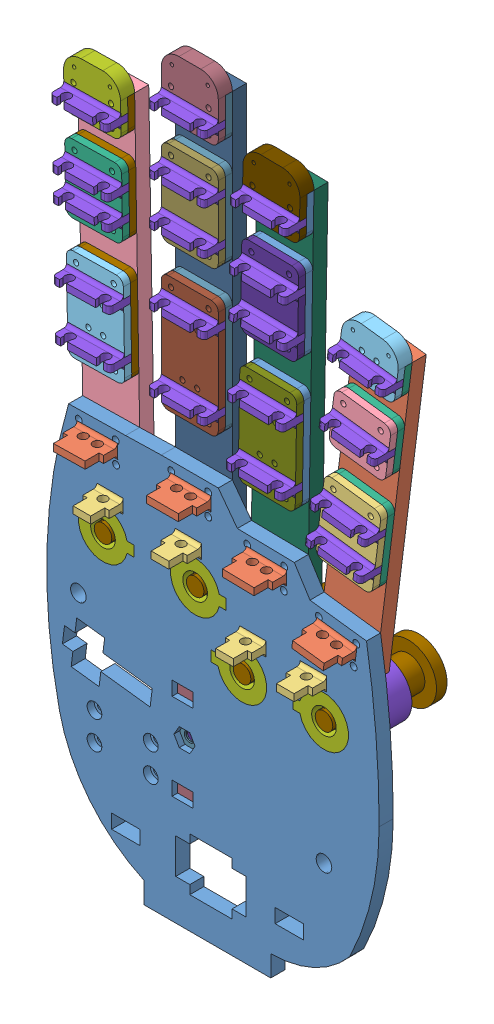
SolidWorks assembly palmUp_fingers_buttons_upPulley, configuration Default. Lengths in mm.
Overall size (100.53 213.84 40.29).
185 component instances, 43 part files, 94 mates.
Components (placement in the parent):
- palmUp-1: palmUp [Default] at (29.1174 30.4931 80.2216) size (94.52 113.2 4)
- driverBaseFrame1-1: driverBaseFrame1 [Default] at (-2.9175 115.1932 80.2216) x (0.999847 0.017467 0) z (0.017467 -0.999847 0) size (11.5 12 4)
- driverBaseFrame1-2: driverBaseFrame1 [Default] at (23.5924 115.6931 80.2216) x (1 0 0) z (0 -1 0) size (11.5 12 4)
- driverBaseFrame1-3: driverBaseFrame1 [Default] at (45.1535 108.3901 80.2216) x (0.999848 -0.017452 0) z (-0.017452 -0.999848 0) size (11.5 12 4)
- driverBaseFrame1-4: driverBaseFrame1 [Default] at (65.1211 100.8452 80.2216) x (0.992117 -0.125312 0) z (-0.125312 -0.992117 0) size (11.5 12 4)
- driverBaseFrame2-1: driverBaseFrame2 [Default] at (-1948.2383 102.6443 -1374.6625) x (1 0 0) z (0 -1 0) size (7.5 12 4)
- driverBaseFrame2-2: driverBaseFrame2 [Default] at (1983.3157 100.6443 -1374.6625) x (-1 0 0) z (0 1 0) size (7.5 12 4)
- driverBaseFrame2-4: driverBaseFrame2 [Default] at (-1907.6963 87.8147 -1374.6625) x (1 0 0) z (0 -1 0) size (7.5 12 4)
- driverBaseFrame2-5: driverBaseFrame2 [Default] at (-1890.412 87.8147 -1374.6625) x (1 0 0) z (0 -1 0) size (7.5 12 4)
- index-1: index [Default] at (-52.494 173.2306 -0.0096) x (-0.999847 -0.017467 0) z (0 0 -1) size (16.2 99.16 12.01)
  - indexElastomer-1: indexElastomer [Default] at (-62.4059 -67.241 -80.2312) size (16.2 94.16 4)
  - indexPIP-1: indexPIP [Default] at (-62.4059 -42.8945 -84.2312) size (16.2 26.26 2)
  - indexMIP-1: indexMIP [Default] at (-62.4059 -8.6345 -84.2312) size (16.2 19.45 2)
  - indexDIP-1: indexDIP [Default] at (-62.4059 16.8205 -84.2312) size (16.2 14.95 4)
  - tubeDriver-6: tubeDriver [Default] at (-62.4059 20.8205 -80.2312) x (1 0 0) z (0 1 0) size (16.2 6 4)
  - tubeDriver-7: tubeDriver [Default] at (-62.4059 3.8205 -80.2312) x (1 0 0) z (0 1 0) size (16.2 6 4)
  - tubeDriver-8: tubeDriver [Default] at (-62.4059 -3.6345 -80.2312) x (1 0 0) z (0 1 0) size (16.2 6 4)
  - tubeDriver-9: tubeDriver [Default] at (-62.4059 -23.6345 -80.2312) x (1 0 0) z (0 1 0) size (16.2 6 4)
  - tubeDriver-10: tubeDriver [Default] at (-62.4059 -37.8945 -80.2312) x (1 0 0) z (0 1 0) size (16.2 6 4)
  - indexTube1-1: indexTube1 [Default] at (-49.2059 -21.6345 -86.4812) x (-0.964902 0 0.26261) z (0 -1 0) size (2.5 2.5 16.26) (hidden)
  - indexTube1-2: indexTube1 [Default] at (-59.4059 -21.6345 -86.4812) x (-0.775159 0 0.631766) z (0 -1 0) size (2.5 2.5 16.26) (hidden)
  - indexTube2-1: indexTube2 [Default] at (-49.2059 5.8205 -86.4812) x (0.360054 0 0.932932) z (0 -1 0) size (2.5 2.5 9.46) (hidden)
  - indexTube2-2: indexTube2 [Default] at (-59.4059 5.8205 -86.4812) x (-0.658969 0 -0.75217) z (0 -1 0) size (2.5 2.5 9.46) (hidden)
  - commonFingersTube-1: commonFingersTube [Default] at (-49.2059 22.8205 -86.4812) x (-0.856421 0 0.516277) z (0 -1 0) size (2.5 2.5 2) (hidden)
  - commonFingersTube-2: commonFingersTube [Default] at (-59.4059 22.8205 -86.4812) x (-0.999231 0 0.039215) z (0 -1 0) size (2.5 2.5 2) (hidden)
  - indexJointBase-1: indexJointBase [Default] at (-62.4059 -67.241 -82.2312) size (16.2 69.66 2)
- middle-1: middle [Default] at (34.8412 175.8995 -30.6566) size (16.2 113.14 12)
  - middleElastomer-1: middleElastomer [Default] at (-13.8237 -68.7065 106.8781) size (16.2 108.14 4)
  - middlePIP-1: middlePIP [Default] at (-13.8237 -44.2065 110.8781) size (16.2 33.21 2)
  - middleMIP-1: middleMIP [Default] at (-13.8237 -2.9965 110.8781) size (16.2 24.45 2)
  - middleDIP-1: middleDIP [Default] at (-5.7237 27.4535 110.8781) size (16.2 16.98 4)
  - tubeDriver-2: tubeDriver [Default] at (-13.8237 33.4535 110.8781) x (1 0 0) z (0 -1 0) size (16.2 6 4)
  - tubeDriver-3: tubeDriver [Default] at (-13.8237 16.4535 110.8781) x (1 0 0) z (0 -1 0) size (16.2 6 4)
  - tubeDriver-4: tubeDriver [Default] at (-13.8237 4.0035 110.8781) x (1 0 0) z (0 -1 0) size (16.2 6 4)
  - tubeDriver-5: tubeDriver [Default] at (-13.8237 -15.9965 110.8781) x (1 0 0) z (0 -1 0) size (16.2 6 4)
  - tubeDriver-6: tubeDriver [Default] at (-13.8237 -37.2065 110.8781) x (1 0 0) z (0 -1 0) size (16.2 6 4)
  - middleTube1-1: middleTube1 [Default] at (-10.8237 -39.2065 117.1281) x (1 0 0) z (0 1 0) size (2.5 2.5 23.21) (hidden)
  - middleTube1-2: middleTube1 [Default] at (-0.6237 -39.2065 117.1281) x (1 0 0) z (0 1 0) size (2.5 2.5 23.21) (hidden)
  - middleTube2-1: middleTube2 [Default] at (-10.8237 2.0035 117.1281) x (1 0 0) z (0 1 0) size (2.5 2.5 14.45) (hidden)
  - middleTube2-2: middleTube2 [Default] at (-0.6237 2.0035 117.1281) x (1 0 0) z (0 1 0) size (2.5 2.5 14.45) (hidden)
  - commonFingersTube-1: commonFingersTube [Default] at (-10.8237 31.4535 117.1281) x (1 0 0) z (0 1 0) size (2.5 2.5 2) (hidden)
  - commonFingersTube-2: commonFingersTube [Default] at (-0.6237 31.4535 117.1281) x (1 0 0) z (0 1 0) size (2.5 2.5 2) (hidden)
  - middleJointBase-1: middleJointBase [Default] at (-13.8237 -70.2065 110.8781) size (16.2 83.64 2)
- ring-1: ring [Default] at (23.5555 139.8292 -20.9472) x (-0.999848 0.017452 0) z (0 0 -1) size (16.2 107.96 12)
  - ringElastomer-1: ringElastomer [Default] at (-35.7683 -39.5573 -101.1688) size (16.2 102.96 4)
  - ringPIP-1: ringPIP [Default] at (-35.7683 -15.0573 -105.1688) size (16.2 29.14 2)
  - ringMIP-1: ringMIP [Default] at (-35.7683 22.0827 -105.1688) size (16.2 23.53 2)
  - ringDIP-1: ringDIP [Default] at (-19.5683 51.6077 -101.1688) x (-1 0 0) z (0 0 -1) size (16.2 16.8 4)
  - tubeDriver-6: tubeDriver [Default] at (-35.7683 55.6077 -101.1688) x (1 0 0) z (0 1 0) size (16.2 6 4)
  - tubeDriver-7: tubeDriver [Default] at (-35.7683 38.6077 -101.1688) x (1 0 0) z (0 1 0) size (16.2 6 4)
  - tubeDriver-8: tubeDriver [Default] at (-35.7683 27.0827 -101.1688) x (1 0 0) z (0 1 0) size (16.2 6 4)
  - tubeDriver-9: tubeDriver [Default] at (-35.7683 7.0827 -101.1688) x (1 0 0) z (0 1 0) size (16.2 6 4)
  - tubeDriver-10: tubeDriver [Default] at (-35.7683 -10.0573 -101.1688) x (1 0 0) z (0 1 0) size (16.2 6 4)
  - ringTube1-1: ringTube1 [Default] at (-22.5683 9.0827 -107.4188) x (1 0 0) z (0 -1 0) size (2.5 2.5 19.14) (hidden)
  - ringTube1-2: ringTube1 [Default] at (-32.7683 9.0827 -107.4188) x (1 0 0) z (0 -1 0) size (2.5 2.5 19.14) (hidden)
  - ringTube2-1: ringTube2 [Default] at (-22.5683 40.6077 -107.4188) x (1 0 0) z (0 -1 0) size (2.5 2.5 13.53) (hidden)
  - ringTube2-2: ringTube2 [Default] at (-32.7683 40.6077 -107.4188) x (1 0 0) z (0 -1 0) size (2.5 2.5 13.53) (hidden)
  - commonFingersTube-1: commonFingersTube [Default] at (-22.5683 57.6077 -107.4188) x (1 0 0) z (0 -1 0) size (2.5 2.5 2) (hidden)
  - commonFingersTube-2: commonFingersTube [Default] at (-32.7683 57.6077 -107.4188) x (-0.448476 0 -0.893795) z (0 -1 0) size (2.5 2.5 2) (hidden)
  - ringJointBase-1: ringJointBase [Default] at (-35.7683 -41.0573 -103.1688) size (16.2 78.46 2)
- pinky-1: pinky [Default] at (76.9532 164.3008 -0.0182) x (0.992117 -0.125312 0) z (0 0 1) size (16.2 89.09 12)
  - pinkyElastomer-1: pinkyElastomer [Default] at (-6.1366 -72.9381 76.2397) size (16.2 84.09 4)
  - pinkyPIP-1: pinkyPIP [Default] at (-6.1366 -48.4381 80.2397) size (16.2 21.74 2)
  - pinkyMIP-1: pinkyMIP [Default] at (-6.1366 -18.6981 80.2397) size (16.2 14.64 2)
  - pinkyDIP-1: pinkyDIP [Default] at (-6.1366 1.9469 80.2397) size (16.2 14.21 4)
  - tubeDriver-5: tubeDriver [Default] at (-6.1366 7.9469 80.2397) x (1 0 0) z (0 -1 0) size (16.2 6 4)
  - tubeDriver-7: tubeDriver [Default] at (-6.1366 -31.6981 80.2397) x (1 0 0) z (0 -1 0) size (16.2 6 4)
  - tubeDriver-8: tubeDriver [Default] at (-6.1366 -41.4381 80.2397) x (1 0 0) z (0 -1 0) size (16.2 6 4)
  - pinkyTube1-1: pinkyTube1 [Default] at (-3.1366 -43.4381 86.4897) x (1 0 0) z (0 1 0) size (2.5 2.5 11.74) (hidden)
  - pinkyTube1-2: pinkyTube1 [Default] at (7.0634 -43.4381 86.4897) x (1 0 0) z (0 1 0) size (2.5 2.5 11.74) (hidden)
  - tubeDriver-10: tubeDriver [Default] at (-6.1366 -10.3756 80.2397) x (1 0 0) z (0 -1 0) size (16.2 6 4)
  - commonFingersTube-1: commonFingersTube [Default] at (-3.1366 5.9469 86.4897) x (1 0 0) z (0 1 0) size (2.5 2.5 2) (hidden)
  - commonFingersTube-2: commonFingersTube [Default] at (7.0634 5.9469 86.4897) x (1 0 0) z (0 1 0) size (2.5 2.5 2) (hidden)
  - pinkyJointBase-1: pinkyJointBase [Default] at (-6.1366 -74.4381 80.2397) size (16.2 59.59 2)
  - commonFingersTube-3: commonFingersTube [Default] at (-3.1366 -12.3756 86.4897) x (1 0 0) z (0 1 0) size (2.5 2.5 2) (hidden)
  - commonFingersTube-4: commonFingersTube [Default] at (7.0634 -12.3756 86.4897) x (1 0 0) z (0 1 0) size (2.5 2.5 2) (hidden)
- buttonBase-1: buttonBase [Default] at (67.2648 77.3147 84.2216) x (0 -1 0) z (0 0 -1) size (16 16.84 9)
- buttonBase-2: buttonBase [Default] at (43.9805 77.3147 84.2216) x (0 -1 0) z (0 0 -1) size (16 16.84 9)
- buttonBase-3: buttonBase [Default] at (30.6388 92.1443 84.2216) x (0 1 0) z (0 0 -1) size (16 16.84 9)
- buttonBase-4: buttonBase [Default] at (4.4385 92.1443 84.2216) x (0 1 0) z (0 0 -1) size (16 16.84 9)
- buttonFrame-1: buttonFrame [Default] at (67.2648 77.3147 67.2216) x (-0.367754 -0.929923 0) z (0 0 1) size (16 16 8)
- buttonFrame-2: buttonFrame [Default] at (43.9805 77.3147 67.2216) x (-0.367754 -0.929923 0) z (0 0 1) size (16 16 8)
- buttonFrame-3: buttonFrame [Default] at (4.4385 92.1443 67.2216) x (-0.366273 -0.930508 0) z (0 0 1) size (16 16 8)
- buttonFrame-4: buttonFrame [Default] at (30.6388 92.1443 67.2216) x (-0.366273 -0.930508 0) z (0 0 1) size (16 16 8)
- buttonAxle-1: buttonAxle [Default] at (67.2648 77.3147 57.2216) size (16 16 27)
- buttonAxle-2: buttonAxle [Default] at (4.4385 92.1443 57.2216) size (16 16 27)
- buttonAxle-3: buttonAxle [Default] at (43.9805 77.3147 57.2216) x (-1 0 0) z (0 0 1) size (16 16 27)
- buttonAxle-4: buttonAxle [Default] at (30.6388 92.1443 57.2216) x (-1 0 0) z (0 0 1) size (16 16 27)
- parallel pin hardened_din-1: parallel pin hardened_din [Parallel Pin ISO 8734 - 2 x 14 - A - St] at (67.5898 69.8147 71.2178) x (0 1 0) z (-0.989175 0 -0.14674) size (14 2 2)
- parallel pin hardened_din-2: parallel pin hardened_din [Parallel Pin ISO 8734 - 2 x 14 - A - St] at (43.6555 69.8147 71.2178) x (0 1 0) z (-0.930242 0 0.366947) size (14 2 2)
- parallel pin hardened_din-3: parallel pin hardened_din [Parallel Pin ISO 8734 - 2 x 14 - A - St] at (4.7635 98.6443 71.2178) x (0 -1 0) z (0 0 1) size (14 2 2)
- parallel pin hardened_din-4: parallel pin hardened_din [Parallel Pin ISO 8734 - 2 x 14 - A - St] at (30.3138 98.6443 71.2178) x (0 -1 0) z (-0.297916 0 0.954592) size (14 2 2)
- Assem1-1: Assem1 [Default] at (68.1098 77.3321 69.8525) x (0.982823 0 0.184551) z (0 -1 0) size (9.07 23.24 9)
  - Spring Part-1: Spring Part [Default] at origin size (9 1 4.5)
  - Spring Part-7: Spring Part [Default] at (-0.0474 0.6138 0) x (0.988155 0.15346 0) z (0 0 -1) size (9 1 4.5)
  - Spring Part-8: Spring Part [Default] at (-0.0474 1.8415 0) x (0.988155 -0.15346 0) z (0 0 1) size (9 1 4.5)
  - Spring Part-9: Spring Part [Default] at (-0.0474 3.0692 0) x (0.988155 0.15346 0) z (0 0 -1) size (9 1 4.5)
  - Spring Part-10: Spring Part [Default] at (-0.0474 4.2969 0) x (0.988155 -0.15346 0) z (0 0 1) size (9 1 4.5)
  - Spring Part-11: Spring Part [Default] at (-0.0474 5.5246 0) x (0.988155 0.15346 0) z (0 0 -1) size (9 1 4.5)
  - Spring Part-12: Spring Part [Default] at (-0.0474 6.7522 0) x (0.988155 -0.15346 0) z (0 0 1) size (9 1 4.5) (hidden)
  - Spring Part-13: Spring Part [Default] at (-0.0474 7.9799 0) x (0.988155 0.15346 0) z (0 0 -1) size (9 1 4.5) (hidden)
  - Spring Part-14: Spring Part [Default] at (-0.0474 9.2076 0) x (0.988155 -0.15346 0) z (0 0 1) size (9 1 4.5) (hidden)
  - Spring Part-15: Spring Part [Default] at (-0.0474 10.4353 0) x (0.988155 0.15346 0) z (0 0 -1) size (9 1 4.5) (hidden)
  - Spring Part-16: Spring Part [Default] at (-0.0474 11.663 0) x (0.988155 -0.15346 0) z (0 0 1) size (9 1 4.5) (hidden)
  - Spring Part-17: Spring Part [Default] at (-0.0474 12.8906 0) x (0.988155 0.15346 0) z (0 0 -1) size (9 1 4.5) (hidden)
  - Spring Part-18: Spring Part [Default] at (-0.0474 14.1183 0) x (0.988155 -0.15346 0) z (0 0 1) size (9 1 4.5) (hidden)
  - Spring Part-19: Spring Part [Default] at (-0.0474 15.346 0) x (0.988155 0.15346 0) z (0 0 -1) size (9 1 4.5) (hidden)
  - Spring Part-20: Spring Part [Default] at (-0.0474 16.5737 0) x (0.988155 -0.15346 0) z (0 0 1) size (9 1 4.5) (hidden)
  - Spring Part-21: Spring Part [Default] at (-0.0474 17.8013 0) x (0.988155 0.15346 0) z (0 0 -1) size (9 1 4.5) (hidden)
  - Spring Part-22: Spring Part [Default] at (-0.0474 19.029 0) x (0.988155 -0.15346 0) z (0 0 1) size (9 1 4.5) (hidden)
  - Spring Part-23: Spring Part [Default] at (-0.0474 20.2567 0) x (0.988155 0.15346 0) z (0 0 -1) size (9 1 4.5) (hidden)
  - Spring Part-24: Spring Part [Default] at (-0.0474 21.4844 0) x (0.988155 -0.15346 0) z (0 0 1) size (9 1 4.5) (hidden)
  - Spring Part-25: Spring Part [Default] at (0 22.0982 0) x (1 0 0) z (0 0 -1) size (9 1 4.5) (hidden)
- Assem1-2: Assem1 [Default] at (43.2323 76.9505 75.7945) x (0.961864 0.191525 0.195284) z (-0.195284 0.980747 0) size (9.07 23.24 9)
  - Spring Part-1: Spring Part [Default] at origin size (9 1 4.5)
  - Spring Part-7: Spring Part [Default] at (-0.0474 0.6138 0) x (0.988155 0.15346 0) z (0 0 -1) size (9 1 4.5)
  - Spring Part-8: Spring Part [Default] at (-0.0474 1.8415 0) x (0.988155 -0.15346 0) z (0 0 1) size (9 1 4.5)
  - Spring Part-9: Spring Part [Default] at (-0.0474 3.0692 0) x (0.988155 0.15346 0) z (0 0 -1) size (9 1 4.5)
  - Spring Part-10: Spring Part [Default] at (-0.0474 4.2969 0) x (0.988155 -0.15346 0) z (0 0 1) size (9 1 4.5)
  - Spring Part-11: Spring Part [Default] at (-0.0474 5.5246 0) x (0.988155 0.15346 0) z (0 0 -1) size (9 1 4.5)
  - Spring Part-12: Spring Part [Default] at (-0.0474 6.7522 0) x (0.988155 -0.15346 0) z (0 0 1) size (9 1 4.5) (hidden)
  - Spring Part-13: Spring Part [Default] at (-0.0474 7.9799 0) x (0.988155 0.15346 0) z (0 0 -1) size (9 1 4.5) (hidden)
  - Spring Part-14: Spring Part [Default] at (-0.0474 9.2076 0) x (0.988155 -0.15346 0) z (0 0 1) size (9 1 4.5) (hidden)
  - Spring Part-15: Spring Part [Default] at (-0.0474 10.4353 0) x (0.988155 0.15346 0) z (0 0 -1) size (9 1 4.5) (hidden)
  - Spring Part-16: Spring Part [Default] at (-0.0474 11.663 0) x (0.988155 -0.15346 0) z (0 0 1) size (9 1 4.5) (hidden)
  - Spring Part-17: Spring Part [Default] at (-0.0474 12.8906 0) x (0.988155 0.15346 0) z (0 0 -1) size (9 1 4.5) (hidden)
  - Spring Part-18: Spring Part [Default] at (-0.0474 14.1183 0) x (0.988155 -0.15346 0) z (0 0 1) size (9 1 4.5) (hidden)
  - Spring Part-19: Spring Part [Default] at (-0.0474 15.346 0) x (0.988155 0.15346 0) z (0 0 -1) size (9 1 4.5) (hidden)
  - Spring Part-20: Spring Part [Default] at (-0.0474 16.5737 0) x (0.988155 -0.15346 0) z (0 0 1) size (9 1 4.5) (hidden)
  - Spring Part-21: Spring Part [Default] at (-0.0474 17.8013 0) x (0.988155 0.15346 0) z (0 0 -1) size (9 1 4.5) (hidden)
  - Spring Part-22: Spring Part [Default] at (-0.0474 19.029 0) x (0.988155 -0.15346 0) z (0 0 1) size (9 1 4.5) (hidden)
  - Spring Part-23: Spring Part [Default] at (-0.0474 20.2567 0) x (0.988155 0.15346 0) z (0 0 -1) size (9 1 4.5) (hidden)
  - Spring Part-24: Spring Part [Default] at (-0.0474 21.4844 0) x (0.988155 -0.15346 0) z (0 0 1) size (9 1 4.5) (hidden)
  - Spring Part-25: Spring Part [Default] at (0 22.0982 0) x (1 0 0) z (0 0 -1) size (9 1 4.5) (hidden)
- Assem1-3: Assem1 [Default] at (30.4884 91.6348 76.0217) x (1 0 0) z (0 1 0) size (9.07 23.24 9)
  - Spring Part-1: Spring Part [Default] at origin size (9 1 4.5)
  - Spring Part-7: Spring Part [Default] at (-0.0474 0.6138 0) x (0.988155 0.15346 0) z (0 0 -1) size (9 1 4.5)
  - Spring Part-8: Spring Part [Default] at (-0.0474 1.8415 0) x (0.988155 -0.15346 0) z (0 0 1) size (9 1 4.5)
  - Spring Part-9: Spring Part [Default] at (-0.0474 3.0692 0) x (0.988155 0.15346 0) z (0 0 -1) size (9 1 4.5)
  - Spring Part-10: Spring Part [Default] at (-0.0474 4.2969 0) x (0.988155 -0.15346 0) z (0 0 1) size (9 1 4.5)
  - Spring Part-11: Spring Part [Default] at (-0.0474 5.5246 0) x (0.988155 0.15346 0) z (0 0 -1) size (9 1 4.5)
  - Spring Part-12: Spring Part [Default] at (-0.0474 6.7522 0) x (0.988155 -0.15346 0) z (0 0 1) size (9 1 4.5) (hidden)
  - Spring Part-13: Spring Part [Default] at (-0.0474 7.9799 0) x (0.988155 0.15346 0) z (0 0 -1) size (9 1 4.5) (hidden)
  - Spring Part-14: Spring Part [Default] at (-0.0474 9.2076 0) x (0.988155 -0.15346 0) z (0 0 1) size (9 1 4.5) (hidden)
  - Spring Part-15: Spring Part [Default] at (-0.0474 10.4353 0) x (0.988155 0.15346 0) z (0 0 -1) size (9 1 4.5) (hidden)
  - Spring Part-16: Spring Part [Default] at (-0.0474 11.663 0) x (0.988155 -0.15346 0) z (0 0 1) size (9 1 4.5) (hidden)
  - Spring Part-17: Spring Part [Default] at (-0.0474 12.8906 0) x (0.988155 0.15346 0) z (0 0 -1) size (9 1 4.5) (hidden)
  - Spring Part-18: Spring Part [Default] at (-0.0474 14.1183 0) x (0.988155 -0.15346 0) z (0 0 1) size (9 1 4.5) (hidden)
  - Spring Part-19: Spring Part [Default] at (-0.0474 15.346 0) x (0.988155 0.15346 0) z (0 0 -1) size (9 1 4.5) (hidden)
  - Spring Part-20: Spring Part [Default] at (-0.0474 16.5737 0) x (0.988155 -0.15346 0) z (0 0 1) size (9 1 4.5) (hidden)
  - Spring Part-21: Spring Part [Default] at (-0.0474 17.8013 0) x (0.988155 0.15346 0) z (0 0 -1) size (9 1 4.5) (hidden)
  - Spring Part-22: Spring Part [Default] at (-0.0474 19.029 0) x (0.988155 -0.15346 0) z (0 0 1) size (9 1 4.5) (hidden)
  - Spring Part-23: Spring Part [Default] at (-0.0474 20.2567 0) x (0.988155 0.15346 0) z (0 0 -1) size (9 1 4.5) (hidden)
  - Spring Part-24: Spring Part [Default] at (-0.0474 21.4844 0) x (0.988155 -0.15346 0) z (0 0 1) size (9 1 4.5) (hidden)
  - Spring Part-25: Spring Part [Default] at (0 22.0982 0) x (1 0 0) z (0 0 -1) size (9 1 4.5) (hidden)
- Assem1-4: Assem1 [Default] at (3.643 90.6443 75.9726) x (1 0 0) z (0 1 0) size (9.07 23.24 9)
  - Spring Part-1: Spring Part [Default] at origin size (9 1 4.5)
  - Spring Part-7: Spring Part [Default] at (-0.0474 0.6138 0) x (0.988155 0.15346 0) z (0 0 -1) size (9 1 4.5)
  - Spring Part-8: Spring Part [Default] at (-0.0474 1.8415 0) x (0.988155 -0.15346 0) z (0 0 1) size (9 1 4.5)
  - Spring Part-9: Spring Part [Default] at (-0.0474 3.0692 0) x (0.988155 0.15346 0) z (0 0 -1) size (9 1 4.5)
  - Spring Part-10: Spring Part [Default] at (-0.0474 4.2969 0) x (0.988155 -0.15346 0) z (0 0 1) size (9 1 4.5)
  - Spring Part-11: Spring Part [Default] at (-0.0474 5.5246 0) x (0.988155 0.15346 0) z (0 0 -1) size (9 1 4.5)
  - Spring Part-12: Spring Part [Default] at (-0.0474 6.7522 0) x (0.988155 -0.15346 0) z (0 0 1) size (9 1 4.5) (hidden)
  - Spring Part-13: Spring Part [Default] at (-0.0474 7.9799 0) x (0.988155 0.15346 0) z (0 0 -1) size (9 1 4.5) (hidden)
  - Spring Part-14: Spring Part [Default] at (-0.0474 9.2076 0) x (0.988155 -0.15346 0) z (0 0 1) size (9 1 4.5) (hidden)
  - Spring Part-15: Spring Part [Default] at (-0.0474 10.4353 0) x (0.988155 0.15346 0) z (0 0 -1) size (9 1 4.5) (hidden)
  - Spring Part-16: Spring Part [Default] at (-0.0474 11.663 0) x (0.988155 -0.15346 0) z (0 0 1) size (9 1 4.5) (hidden)
  - Spring Part-17: Spring Part [Default] at (-0.0474 12.8906 0) x (0.988155 0.15346 0) z (0 0 -1) size (9 1 4.5) (hidden)
  - Spring Part-18: Spring Part [Default] at (-0.0474 14.1183 0) x (0.988155 -0.15346 0) z (0 0 1) size (9 1 4.5) (hidden)
  - Spring Part-19: Spring Part [Default] at (-0.0474 15.346 0) x (0.988155 0.15346 0) z (0 0 -1) size (9 1 4.5) (hidden)
  - Spring Part-20: Spring Part [Default] at (-0.0474 16.5737 0) x (0.988155 -0.15346 0) z (0 0 1) size (9 1 4.5) (hidden)
  - Spring Part-21: Spring Part [Default] at (-0.0474 17.8013 0) x (0.988155 0.15346 0) z (0 0 -1) size (9 1 4.5) (hidden)
  - Spring Part-22: Spring Part [Default] at (-0.0474 19.029 0) x (0.988155 -0.15346 0) z (0 0 1) size (9 1 4.5) (hidden)
  - Spring Part-23: Spring Part [Default] at (-0.0474 20.2567 0) x (0.988155 0.15346 0) z (0 0 -1) size (9 1 4.5) (hidden)
  - Spring Part-24: Spring Part [Default] at (-0.0474 21.4844 0) x (0.988155 -0.15346 0) z (0 0 1) size (9 1 4.5) (hidden)
  - Spring Part-25: Spring Part [Default] at (0 22.0982 0) x (1 0 0) z (0 0 -1) size (9 1 4.5) (hidden)
- SupportPulleyPalmUpAssem-1: SupportPulleyPalmUpAssem [Default] at (18.0404 39.4745 49.5054) size (10 28.63 10)
  - supportPulleyPalmUp2-1: supportPulleyPalmUp2 [Default] at (10.0404 13.9256 23.1162) size (7.5 28.63 2)
  - supportPulleyPalmUp-1: supportPulleyPalmUp [Default] at (12.0404 26.3656 33.1162) x (-1 0 0) z (0 -1 0) size (10 10 4)
  - supportPulleyPalmUp-2: supportPulleyPalmUp [Default] at (12.0404 1.7356 33.1162) x (-1 0 0) z (0 -1 0) size (10 10 4)
- hex nut style 1 gradeab_din-1: hex nut style 1 gradeab_din [Hexagon Nut ISO 4032 - M3 - D - S] at (27.442 52.7975 82.6216) x (0 1 0) z (0 0 1) size (5.5 6.35 2.4)
- plain washer 6902 type abc_din-1: plain washer 6902 type abc_din [DIN 6902-C3.2] at (28.0808 53.4001 80.2216) x (0 0 -1) z (0.195239 0.980756 0) size (0.8 7 7)
- pulley-1: pulley [Default] at (28.0808 53.4001 75.4216) x (0.991013 -0.133768 0) z (0 0 1) size (12 12 4)
- plain washer 6902 type abc_din-2: plain washer 6902 type abc_din [DIN 6902-C3.2] at (28.0808 53.4001 75.4216) x (0 0 -1) z (0.978291 0.207235 0) size (0.8 7 7)
- socket head cap screw 4762_din-1: socket head cap screw 4762_din [ISO 4762 M3 x 10 --- 10S] at (28.0808 53.4001 69.6216) x (0 0 1) z (-0.999894 -0.01457 0) size (13 5.5 5.5)
Mates (geometry in assembly coordinates):
- Coincident1: coincident anti-aligned: plane of palmUp-1 through (-1.6321 113.2154 84.2216) normal (-0.017467 0.999847 0); plane of driverBaseFrame1-1 through (-2.8826 113.1935 80.2216) normal (0.017467 -0.999847 0)
- Coincident2: coincident anti-aligned: plane of palmUp-1 through (7.3666 113.3726 84.2216) normal (-0.999847 -0.017467 0); plane of driverBaseFrame1-1 through (7.3666 113.3726 84.2216) normal (0.999847 0.017467 0)
- Coincident3: coincident aligned: plane of palmUp-1 through (143.3195 75.6611 80.2216) normal (0 0 -1); plane of driverBaseFrame1-1 through (-1.6328 113.2154 80.2216) normal (0 0 -1)
- Coincident4: coincident anti-aligned: plane of palmUp-1 through (24.8424 113.6931 84.2216) normal (0 1 0); plane of driverBaseFrame1-2 through (23.5924 113.6931 80.2216) normal (0 -1 0)
- Coincident5: coincident anti-aligned: plane of palmUp-1 through (24.8424 115.6931 84.2216) normal (1 0 0); plane of driverBaseFrame1-2 through (24.8424 113.6931 84.2216) normal (-1 0 0)
- Coincident6: coincident aligned: plane of palmUp-1 through (143.3195 75.6611 80.2216) normal (0 0 -1); plane of driverBaseFrame1-2 through (24.8424 113.6931 80.2216) normal (0 0 -1)
- Coincident7: coincident aligned: plane of palmUp-1 through (143.3195 75.6611 80.2216) normal (0 0 -1); plane of driverBaseFrame1-3 through (46.3684 106.3686 80.2216) normal (0 0 -1)
- Coincident8: coincident anti-aligned: plane of palmUp-1 through (54.952 108.2191 84.2216) normal (-0.017452 -0.999848 0); plane of driverBaseFrame1-3 through (45.1535 108.3901 80.2216) normal (0.017452 0.999848 0)
- Coincident12: coincident anti-aligned: plane of palmUp-1 through (46.4033 108.3683 84.2216) normal (0.999848 -0.017452 0); plane of driverBaseFrame1-3 through (46.3684 106.3686 84.2216) normal (-0.999848 0.017452 0)
- Coincident13: coincident anti-aligned: plane of palmUp-1 through (66.1107 98.7043 84.2216) normal (0.125312 0.992117 0); plane of driverBaseFrame1-4 through (64.8705 98.861 80.2216) normal (-0.125312 -0.992117 0)
- Coincident14: coincident aligned: plane of palmUp-1 through (143.3195 75.6611 80.2216) normal (0 0 -1); plane of driverBaseFrame1-4 through (66.1107 98.7043 80.2216) normal (0 0 -1)
- Coincident15: coincident anti-aligned: plane of palmUp-1 through (66.3613 100.6886 84.2216) normal (0.992117 -0.125312 0); plane of driverBaseFrame1-4 through (66.1107 98.7043 84.2216) normal (-0.992117 0.125312 0)
- Coincident16: coincident anti-aligned: plane of palmUp-1 through (3.9385 100.6443 84.2216) normal (0 1 0); plane of driverBaseFrame2-1 through (-1948.2383 100.6443 -1374.6625) normal (0 -1 0)
- Coincident17: coincident aligned: plane of palmUp-1 through (143.3195 75.6611 80.2216) normal (0 0 -1); plane of driverBaseFrame2-1 through (3.9385 100.6443 80.2216) normal (0 0 -1)
- Coincident18: coincident anti-aligned: plane of palmUp-1 through (3.9385 102.6443 84.2216) normal (1 0 0); plane of driverBaseFrame2-1 through (3.9385 100.6443 84.2216) normal (-1 0 0)
- Distance1: distance = 0 mm aligned: plane of palmUp-1 through (143.3195 75.6611 80.2216) normal (0 0 -1); plane of driverBaseFrame2-2 through (31.1388 102.6443 80.2216) normal (0 0 -1)
- Coincident20: coincident anti-aligned: plane of palmUp-1 through (31.1388 100.6443 84.2216) normal (-1 0 0); plane of driverBaseFrame2-2 through (31.1388 102.6443 84.2216) normal (1 0 0)
- Coincident21: coincident anti-aligned: plane of palmUp-1 through (26.1388 102.6443 84.2216) normal (0 -1 0); plane of driverBaseFrame2-2 through (1983.3157 102.6443 -1374.6625) normal (0 1 0)
- Coincident22: coincident anti-aligned: plane of palmUp-1 through (44.4805 85.8147 84.2216) normal (0 1 0); plane of driverBaseFrame2-4 through (-1907.6963 85.8147 -1374.6625) normal (0 -1 0)
- Coincident23: coincident aligned: plane of palmUp-1 through (143.3195 75.6611 80.2216) normal (0 0 -1); plane of driverBaseFrame2-4 through (44.4805 85.8147 80.2216) normal (0 0 -1)
- Coincident24: coincident anti-aligned: plane of palmUp-1 through (49.4805 85.8147 84.2216) normal (-1 0 0); plane of driverBaseFrame2-4 through (49.4805 85.8147 84.2216) normal (1 0 0)
- Coincident25: coincident anti-aligned: plane of palmUp-1 through (61.7648 85.8147 84.2216) normal (0 1 0); plane of driverBaseFrame2-5 through (-1890.412 85.8147 -1374.6625) normal (0 -1 0)
- Coincident26: coincident aligned: plane of palmUp-1 through (143.3195 75.6611 80.2216) normal (0 0 -1); plane of driverBaseFrame2-5 through (61.7648 85.8147 80.2216) normal (0 0 -1)
- Coincident27: coincident anti-aligned: plane of palmUp-1 through (61.7648 87.8147 84.2216) normal (1 0 0); plane of driverBaseFrame2-5 through (61.7648 85.8147 84.2216) normal (-1 0 0)
- Concentric1: concentric anti-aligned: cylinder of palmUp-1 through (8.0553 116.8851 84.2216) axis (0 0 -1) radius 0.975; cylinder of index-1/indexElastomer-1 through (8.0553 116.8851 76.2216) axis (0 0 1) radius 0.5
- Concentric2: concentric anti-aligned: cylinder of palmUp-1 through (8.1601 110.886 84.2216) axis (0 0 -1) radius 0.975; cylinder of index-1/indexElastomer-1 through (8.1601 110.886 76.2216) axis (0 0 1) radius 0.5
- Coincident28: coincident anti-aligned: plane of palmUp-1 through (143.3195 75.6611 80.2216) normal (0 0 -1); plane of index-1/indexElastomer-1 through (11.0769 107.0899 80.2216) normal (0 0 1)
- Concentric3: concentric aligned: cylinder of palmUp-1 through (23.8674 111.1931 84.2216) axis (0 0 -1) radius 0.975; cylinder of middle-1/middleElastomer-1 through (23.8674 111.1931 80.2216) axis (0 0 -1) radius 0.52
- Concentric4: concentric aligned: circle of palmUp-1; circle of middle-1/middleElastomer-1
- Coincident29: coincident anti-aligned: plane of palmUp-1 through (143.3195 75.6611 80.2216) normal (0 0 -1); plane of middle-1/middleElastomer-1 through (21.0174 107.1931 80.2216) normal (0 0 1)
- Concentric5: concentric aligned: circle of palmUp-1; cylinder of ring-1/ringElastomer-1 through (45.3499 103.886 76.2216) axis (0 0 1) radius 0.5
- Concentric6: concentric anti-aligned: cylinder of palmUp-1 through (45.4546 109.8851 84.2216) axis (0 0 -1) radius 0.975; cylinder of ring-1/ringElastomer-1 through (45.4546 109.8851 76.2216) axis (0 0 1) radius 0.5
- Coincident30: coincident anti-aligned: plane of palmUp-1 through (143.3195 75.6611 80.2216) normal (0 0 -1); plane of ring-1/ringElastomer-1 through (58.628 99.6536 80.2216) normal (0 0 1)
- Concentric7: concentric aligned: cylinder of palmUp-1 through (65.0537 96.318 84.2216) axis (0 0 -1) radius 0.975; cylinder of pinky-1/pinkyElastomer-1 through (65.0537 96.318 80.2216) axis (0 0 -1) radius 0.52
- Concentric8: concentric anti-aligned: cylinder of palmUp-1 through (65.8055 102.2707 84.2216) axis (0 0 -1) radius 0.975; circle of pinky-1/pinkyElastomer-1
- Coincident31: coincident anti-aligned: plane of palmUp-1 through (143.3195 75.6611 80.2216) normal (0 0 -1); plane of pinky-1/pinkyElastomer-1 through (61.7249 92.7066 80.2216) normal (0 0 1)
- Concentric9: concentric anti-aligned: cylinder of palmUp-1 through (67.2648 77.3147 84.2216) axis (0 0 -1) radius 7; cylinder of buttonBase-1 through (67.2648 77.3147 80.2216) axis (0 0 1) radius 7
- Coincident32: coincident: moEndPointRef_w of palmUp-1; plane of buttonBase-1 through (60.4274 75.8147 80.2216) normal (0 -1 0)
- Coincident40: coincident anti-aligned: plane of palmUp-1 through (143.3195 75.6611 80.2216) normal (0 0 -1); plane of buttonBase-1 through (67.2648 77.3147 80.2216) normal (0 0 1)
- Concentric10: concentric anti-aligned: cylinder of palmUp-1 through (43.9805 77.3147 84.2216) axis (0 0 -1) radius 7; cylinder of buttonBase-2 through (43.9805 77.3147 80.2216) axis (0 0 1) radius 7
- Coincident34: coincident anti-aligned: plane of palmUp-1 through (35.1431 75.8147 84.2216) normal (0 1 0); plane of buttonBase-2 through (37.1431 75.8147 80.2216) normal (0 -1 0)
- Coincident41: coincident anti-aligned: plane of palmUp-1 through (143.3195 75.6611 80.2216) normal (0 0 -1); plane of buttonBase-2 through (43.9805 77.3147 80.2216) normal (0 0 1)
- Concentric11: concentric anti-aligned: cylinder of palmUp-1 through (30.6388 92.1443 84.2216) axis (0 0 -1) radius 7; cylinder of buttonBase-3 through (30.6388 92.1443 80.2216) axis (0 0 1) radius 7
- Coincident37: coincident anti-aligned: plane of palmUp-1 through (39.4762 90.6443 84.2216) normal (0 1 0); plane of buttonBase-3 through (38.497 90.6443 80.2216) normal (0 -1 0)
- Coincident42: coincident anti-aligned: plane of palmUp-1 through (143.3195 75.6611 80.2216) normal (0 0 -1); plane of buttonBase-3 through (30.6388 92.1443 80.2216) normal (0 0 1)
- Concentric13: concentric anti-aligned: cylinder of palmUp-1 through (4.4385 92.1443 84.2216) axis (0 0 -1) radius 7; cylinder of buttonBase-4 through (4.4385 92.1443 80.2216) axis (0 0 1) radius 7
- Coincident39: coincident anti-aligned: plane of palmUp-1 through (11.2759 93.6443 84.2216) normal (0 -1 0); plane of buttonBase-4 through (11.2759 93.6443 80.2216) normal (0 1 0)
- Coincident43: coincident anti-aligned: plane of palmUp-1 through (143.3195 75.6611 80.2216) normal (0 0 -1); plane of buttonBase-4 through (4.4385 92.1443 80.2216) normal (0 0 1)
- Concentric14: concentric anti-aligned: cylinder of buttonBase-1 through (67.2648 77.3147 75.2216) axis (0 0 1) radius 5; cylinder of buttonFrame-1 through (67.2648 77.3147 75.2216) axis (0 0 -1) radius 5
- Coincident44: coincident aligned: plane of buttonBase-1 through (63.4238 70.2971 76.2216) normal (0.877201 -0.480124 0); plane of buttonFrame-1 through (63.4238 70.2971 72.7216) normal (0.877201 -0.480124 0)
- Coincident60: coincident anti-aligned: plane of buttonBase-1 through (67.2648 77.3147 75.2216) normal (0 0 -1); plane of buttonFrame-1 through (67.2648 77.3147 75.2216) normal (0 0 1)
- Concentric15: concentric anti-aligned: cylinder of buttonBase-2 through (43.9805 77.3147 75.2216) axis (0 0 1) radius 5; cylinder of buttonFrame-2 through (43.9805 77.3147 75.2216) axis (0 0 -1) radius 5
- Coincident46: coincident: line of buttonBase-2 through (41.5799 72.9287 77.2216) axis (-0.480124 -0.877201 0); plane of buttonFrame-2 through (40.1395 70.2971 72.7216) normal (0.877201 -0.480124 0)
- Coincident61: coincident anti-aligned: plane of buttonBase-2 through (43.9805 77.3147 75.2216) normal (0 0 -1); plane of buttonFrame-2 through (43.9805 77.3147 75.2216) normal (0 0 1)
- Concentric16: concentric anti-aligned: cylinder of buttonBase-3 through (30.6388 92.1443 75.2216) axis (0 0 1) radius 5; cylinder of buttonFrame-4 through (30.6388 92.1443 75.2216) axis (0 0 -1) radius 5
- Parallel1: parallel aligned: plane of buttonBase-4 through (0.6087 85.1206 76.2216) normal (0.877964 -0.478727 0); plane of buttonFrame-4 through (26.809 85.1206 72.7216) normal (0.877964 -0.478727 0)
- Coincident63: coincident anti-aligned: plane of buttonBase-4 through (4.4385 92.1443 75.2216) normal (0 0 -1); plane of buttonFrame-4 through (30.6388 92.1443 75.2216) normal (0 0 1)
- Concentric17: concentric anti-aligned: cylinder of buttonBase-4 through (4.4385 92.1443 75.2216) axis (0 0 1) radius 5; cylinder of buttonFrame-3 through (4.4385 92.1443 75.2216) axis (0 0 -1) radius 5
- Coincident50: coincident aligned: plane of buttonBase-4 through (0.6087 85.1206 76.2216) normal (0.877964 -0.478727 0); plane of buttonFrame-3 through (0.6087 85.1206 72.7216) normal (0.877964 -0.478727 0)
- Coincident62: coincident anti-aligned: plane of buttonBase-4 through (4.4385 92.1443 75.2216) normal (0 0 -1); plane of buttonFrame-3 through (4.4385 92.1443 75.2216) normal (0 0 1)
- Concentric18: concentric aligned: cylinder of buttonFrame-1 through (67.2648 77.3147 75.2216) axis (0 0 -1) radius 5; cylinder of buttonAxle-1 through (67.2648 77.3147 74.2216) axis (0 0 -1) radius 4.675
- Distance6: distance = 7 mm anti-aligned: plane of buttonAxle-1 through (67.2648 77.3147 74.2216) normal (0 0 1); plane of buttonFrame-1 through (67.2648 77.3147 67.2216) normal (0 0 -1)
- Concentric19: concentric aligned: cylinder of buttonFrame-2 through (43.9805 77.3147 75.2216) axis (0 0 -1) radius 5; cylinder of buttonAxle-3 through (43.9805 77.3147 74.2216) axis (0 0 -1) radius 4.675
- Distance7: distance = 7 mm anti-aligned: plane of buttonFrame-2 through (43.9805 77.3147 67.2216) normal (0 0 -1); plane of buttonAxle-3 through (43.9805 77.3147 74.2216) normal (0 0 1)
- Concentric20: concentric aligned: cylinder of buttonFrame-4 through (30.6388 92.1443 75.2216) axis (0 0 -1) radius 5; cylinder of buttonAxle-4 through (30.6388 92.1443 74.2216) axis (0 0 -1) radius 4.675
- Distance8: distance = 7 mm anti-aligned: plane of buttonFrame-4 through (30.6388 92.1443 67.2216) normal (0 0 -1); plane of buttonAxle-4 through (30.6388 92.1443 74.2216) normal (0 0 1)
- Concentric21: concentric aligned: cylinder of buttonFrame-3 through (4.4385 92.1443 75.2216) axis (0 0 -1) radius 5; cylinder of buttonAxle-2 through (4.4385 92.1443 74.2216) axis (0 0 -1) radius 4.675
- Distance9: distance = 7 mm anti-aligned: plane of buttonFrame-3 through (4.4385 92.1443 67.2216) normal (0 0 -1); plane of buttonAxle-2 through (4.4385 92.1443 74.2216) normal (0 0 1)
- Concentric22: concentric anti-aligned: cylinder of buttonAxle-1 through (67.5898 69.8147 71.2178) axis (0 1 0) radius 1.225; cylinder of parallel pin hardened_din-1 through (67.5898 63.4647 71.2178) axis (0 -1 0) radius 1
- Distance10: distance = 6 mm aligned: plane of parallel pin hardened_din-1 through (67.7227 69.8147 70.3214) normal (0 -1 0); plane of buttonBase-1 through (60.4274 75.8147 80.2216) normal (0 -1 0)
- Concentric23: concentric aligned: cylinder of buttonAxle-3 through (43.6555 84.8147 71.2178) axis (0 -1 0) radius 1.225; cylinder of parallel pin hardened_din-2 through (43.6555 63.4647 71.2178) axis (0 -1 0) radius 1
- Distance11: distance = 8 mm anti-aligned: plane of parallel pin hardened_din-2 through (43.6555 83.8147 71.2178) normal (0 1 0); plane of buttonBase-2 through (37.1431 75.8147 80.2216) normal (0 -1 0)
- Concentric24: concentric anti-aligned: cylinder of buttonAxle-4 through (30.3138 99.6443 71.2178) axis (0 -1 0) radius 1.225; cylinder of parallel pin hardened_din-4 through (30.3138 104.9943 71.2178) axis (0 1 0) radius 1
- Distance12: distance = 6 mm aligned: plane of parallel pin hardened_din-4 through (30.3138 84.6443 71.2178) normal (0 -1 0); plane of buttonBase-3 through (38.497 90.6443 80.2216) normal (0 -1 0)
- Concentric25: concentric aligned: cylinder of buttonAxle-2 through (4.7635 84.6443 71.2178) axis (0 1 0) radius 1.225; cylinder of parallel pin hardened_din-3 through (4.7635 104.9943 71.2178) axis (0 1 0) radius 1
- Distance13: distance = 6 mm aligned: plane of parallel pin hardened_din-3 through (4.7635 84.6443 71.2178) normal (0 -1 0); plane of buttonBase-4 through (12.2966 90.6443 80.2216) normal (0 -1 0)
- Parallel2: parallel anti-aligned: plane of buttonBase-1 through (60.4274 75.8147 80.2216) normal (0 -1 0); plane of Assem1-1/Spring Part-11 through (70.8151 77.3321 76.6062) normal (0 1 0)
- Parallel3: parallel: line of buttonBase-2 through (36.1224 75.8147 75.2216) axis (0 0 1); plane of Assem1-2/Spring Part-1 through (47.0797 77.7166 76.5756) normal (-0.195284 0.980747 0)
- Parallel4: parallel anti-aligned: plane of buttonBase-3 through (38.497 90.6443 80.2216) normal (0 -1 0); plane of Assem1-3/Spring Part-1 through (34.4884 91.6348 76.0217) normal (0 1 0)
- Coincident59: coincident anti-aligned: plane of buttonBase-4 through (12.2966 90.6443 80.2216) normal (0 -1 0); plane of Assem1-4/Spring Part-1 through (7.643 90.6443 75.9726) normal (0 1 0)
- Coincident64: coincident anti-aligned: plane of palmUp-1 through (30.0808 37.2101 84.2216) normal (0 1 0); plane of SupportPulleyPalmUpAssem-1/supportPulleyPalmUp-2 through (30.0808 37.2101 82.6216) normal (0 -1 0)
- Coincident65: coincident anti-aligned: plane of palmUp-1 through (24.0808 37.2101 84.2216) normal (1 0 0); plane of SupportPulleyPalmUpAssem-1/supportPulleyPalmUp-2 through (24.0808 37.2101 82.6216) normal (-1 0 0)
- Coincident67: coincident anti-aligned: plane of palmUp-1 through (29.1174 50.1994 84.2216) normal (-0.866025 0.5 0); plane of hex nut style 1 gradeab_din-1 through (29.0297 50.0475 80.2216) normal (0.866025 -0.5 0)
- Coincident68: coincident anti-aligned: plane of palmUp-1 through (30.6174 52.7975 84.2216) normal (-0.866025 -0.5 0); plane of hex nut style 1 gradeab_din-1 through (30.6174 52.7975 80.2216) normal (0.866025 0.5 0)
- Coincident69: coincident aligned: plane of palmUp-1 through (143.3195 75.6611 80.2216) normal (0 0 -1); plane of hex nut style 1 gradeab_din-1 through (24.2666 52.7975 80.2216) normal (0 0 -1)
- Concentric26: concentric anti-aligned: cylinder of SupportPulleyPalmUpAssem-1/supportPulleyPalmUp2-1 through (28.0808 53.4001 74.6216) axis (0 0 -1) radius 1.5; cylinder of plain washer 6902 type abc_din-1 through (28.0808 53.4001 79.4216) axis (0 0 1) radius 1.6
- Coincident70: coincident anti-aligned: plane of hex nut style 1 gradeab_din-1 through (24.2666 52.7975 80.2216) normal (0 0 -1); plane of plain washer 6902 type abc_din-1 through (28.0808 53.4001 80.2216) normal (0 0 1)
- Concentric27: concentric aligned: cylinder of SupportPulleyPalmUpAssem-1/supportPulleyPalmUp2-1 through (28.0808 53.4001 74.6216) axis (0 0 -1) radius 1.5; cylinder of pulley-1 through (28.0808 53.4001 77.4216) axis (0 0 -1) radius 1.5
- Coincident71: coincident anti-aligned: plane of plain washer 6902 type abc_din-1 through (28.0808 53.4001 79.4216) normal (0 0 -1); plane of pulley-1 through (28.0808 53.4001 79.4216) normal (0 0 1)
- Concentric28: concentric anti-aligned: cylinder of pulley-1 through (28.0808 53.4001 77.4216) axis (0 0 -1) radius 1.5; cylinder of plain washer 6902 type abc_din-2 through (28.0808 53.4001 74.6216) axis (0 0 1) radius 1.6
- Coincident72: coincident anti-aligned: plane of pulley-1 through (28.0808 53.4001 75.4216) normal (0 0 -1); plane of plain washer 6902 type abc_din-2 through (28.0808 53.4001 75.4216) normal (0 0 1)
- Coincident73: coincident anti-aligned: plane of SupportPulleyPalmUpAssem-1/supportPulleyPalmUp2-1 through (28.0808 53.4001 74.6216) normal (0 0 1); plane of plain washer 6902 type abc_din-2 through (28.0808 53.4001 74.6216) normal (0 0 -1)
- Coincident74: coincident aligned: cylinder of SupportPulleyPalmUpAssem-1/supportPulleyPalmUp2-1 through (28.0808 53.4001 74.6216) axis (0 0 -1) radius 1.5; circle of socket head cap screw 4762_din-1
- Coincident75: coincident anti-aligned: plane of SupportPulleyPalmUpAssem-1/supportPulleyPalmUp2-1 through (28.0808 53.4001 72.6216) normal (0 0 -1); plane of socket head cap screw 4762_din-1 through (28.0407 56.1498 72.6216) normal (0 0 1)
